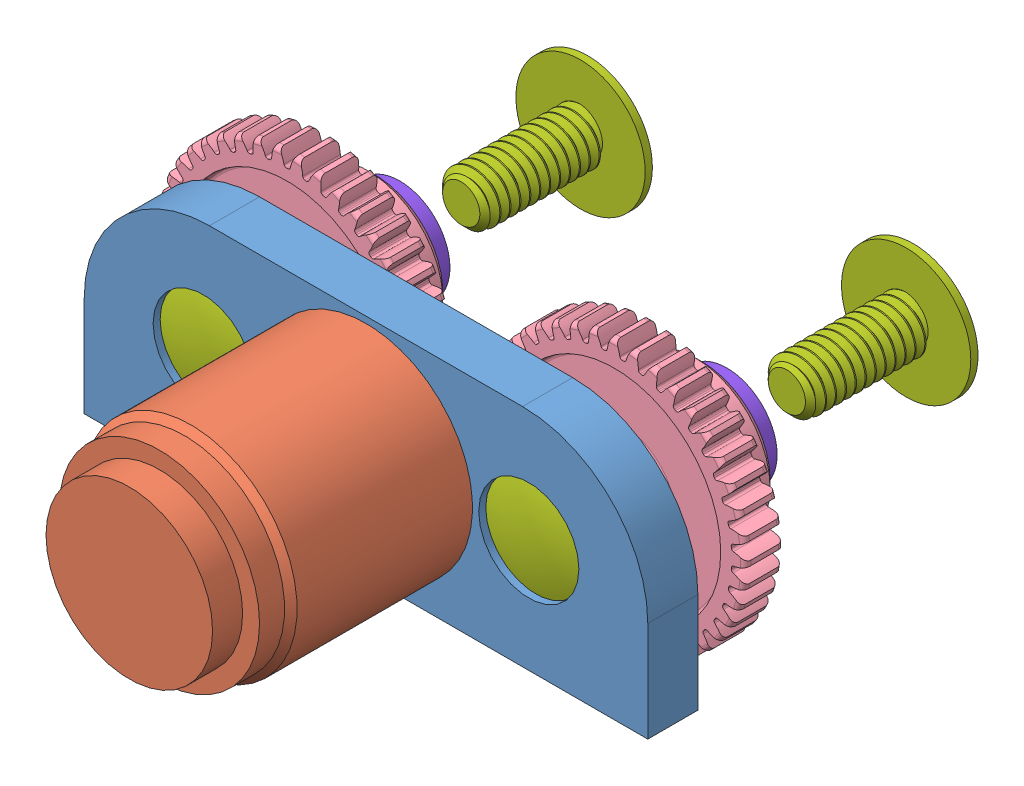
SolidWorks assembly motorassembly, configuration Default. Lengths in mm.
Overall size (55.17 29.38 50.59).
19 component instances, 9 part files, 31 mates.
Components (placement in the parent):
- smallmotormount-1: smallmotormount [Default] at (9.374 -3.21 4.9927) size (45 18 4)
- 1717SR-1: 1717SR [Default] at (-13.126 5.79 4.4927) size (17 17 28.5)
- 12g-1: 12g [Default] at (-13.126 5.79 -2.1073) x (0 0 1) z (-0.828983 0.559273 0) size (7.03 7.06 7.06)
- 40toothgearmod-1: 40toothgearmod [Default] at (-0.126 5.79 -3.3323) x (0 0 -1) z (0.582508 0.812825 0) size (7.03 21.05 21.05)
- 7804K104-1: 7804K104 [7804K104] at (-0.126 5.79 -3.2573) size (8 8 2.5)
- 7804K104-2: 7804K104 [7804K104] at (-0.126 5.79 -7.7073) size (8 8 2.5)
- 3mm spacer-1: 3mm spacer [93657A034] at (-0.126 5.79 -0.5073) x (0.468841 0.883283 0) z (0 0 1) size (8 8 3)
- 3mm spacer-2: 3mm spacer [93657A034] at (-26.126 5.79 -0.5073) size (8 8 3)
- 40toothgearmod-2: 40toothgearmod [Default] at (-26.126 5.79 -3.2073) x (0 0 -1) z (-0.852435 0.522834 0) size (7.03 21.05 21.05)
- 7804K104-3: 7804K104 [7804K104] at (-26.126 5.79 -7.4573) x (0.989675 -0.143329 0) z (0 0 1) size (8 8 2.5)
- 7804K104-4: 7804K104 [7804K104] at (-26.126 5.79 -3.5573) size (8 8 2.5)
- 93121A335-5: 93121A335 [93121A335] at (-26.126 5.79 -15.6123) x (0 0 -1) z (1 0 0) size (31.72 10.32 10.32)
- 93121A335-6: 93121A335 [93121A335] at (-0.126 5.79 -15.6123) x (0 0 -1) z (1 0 0) size (31.72 10.32 10.32)
- 2mm spacer-4: 2mm spacer [93657A031] at (-26.126 5.79 -9.7073) size (8 8 2)
- 2mm spacer-5: 2mm spacer [93657A031] at (-0.126 5.79 -9.8323) x (0.998742 -0.050146 0) z (0 0 1) size (8 8 2)
- 91430A003-1: 91430A003 [91430A003] at (-17.4561 3.29 1.9527) x (-0.81438 0.580333 0) z (0 0 -1) size (2.98 3 6.04)
- 91430A003-2: 91430A003 [91430A003] at (-8.7958 3.29 1.9527) x (-0.681464 0.731852 0) z (0 0 -1) size (2.98 3 6.04)
- 91430A003-3: 91430A003 [91430A003] at (-17.4561 8.29 1.9527) x (-0.939603 0.342267 0) z (0 0 -1) size (2.98 3 6.04)
- 91430A003-4: 91430A003 [91430A003] at (-8.7958 8.29 1.9527) x (-0.743466 0.668774 0) z (0 0 -1) size (2.98 3 6.04)
Mates (geometry in assembly coordinates):
- Concentric5: concentric aligned: cylinder of 1717SR-1 through (-13.126 5.79 -4.6073) axis (0 0 1) radius 0.75; cylinder of 12g-1 through (-13.126 5.79 -0.3073) axis (0 0 1) radius 1
- Concentric10: concentric anti-aligned: cylinder of 40toothgearmod-1 through (-0.126 5.79 -1.8035) axis (0 0 -1) radius 4; cylinder of 7804K104-1 through (-0.126 5.79 -2.0073) axis (0 0 1) radius 4
- Coincident13: coincident aligned: circle of 40toothgearmod-1; circle of 7804K104-1
- Concentric11: concentric anti-aligned: cylinder of 40toothgearmod-1 through (-0.126 5.79 -1.8035) axis (0 0 -1) radius 4; cylinder of 7804K104-2 through (-0.126 5.79 -6.4573) axis (0 0 1) radius 4
- Coincident14: coincident anti-aligned: circle of 40toothgearmod-1; circle of 7804K104-2
- Coincident23: coincident anti-aligned: plane of smallmotormount-1 through (9.374 14.79 0.9927) normal (0 0 -1); plane of 3mm spacer-1 through (-0.126 5.79 0.9927) normal (0 0 1)
- Coincident24: coincident anti-aligned: plane of 7804K104-1 through (-0.126 9.665 -2.0073) normal (0 0 1); plane of 3mm spacer-1 through (-0.126 5.79 -2.0073) normal (0 0 -1)
- Coincident26: coincident anti-aligned: plane of smallmotormount-1 through (9.374 14.79 0.9927) normal (0 0 -1); plane of 3mm spacer-2 through (-26.126 5.79 0.9927) normal (0 0 1)
- Coincident27: coincident anti-aligned: plane of 3mm spacer-2 through (-26.126 5.79 -2.0073) normal (0 0 -1); circle of 40toothgearmod-2
- Concentric22: concentric anti-aligned: cylinder of 40toothgearmod-2 through (-26.126 5.79 -1.6785) axis (0 0 -1) radius 4; cylinder of 7804K104-4 through (-26.126 5.79 -2.3073) axis (0 0 1) radius 4
- Concentric23: concentric aligned: circle of 40toothgearmod-2; circle of 7804K104-4
- Coincident28: coincident aligned: plane of 40toothgearmod-2 through (-26.126 5.79 -2.3073) normal (0 0 1); plane of 7804K104-4 through (-26.126 8.7983 -2.3073) normal (0 0 1)
- Concentric24: concentric anti-aligned: cylinder of 40toothgearmod-2 through (-26.126 5.79 -1.6785) axis (0 0 -1) radius 4; cylinder of 7804K104-3 through (-26.126 5.79 -6.2073) axis (0 0 1) radius 4
- Coincident30: coincident aligned: plane of 40toothgearmod-2 through (-26.126 5.79 -8.7073) normal (0 0 -1); plane of 7804K104-3 through (-25.7497 8.3879 -8.7073) normal (0 0 -1)
- Coincident31: coincident anti-aligned: plane of smallmotormount-1 through (-26.126 5.79 3.4377) normal (0 0 1); plane of 93121A335-5 through (-26.126 5.79 3.4377) normal (0 0 -1)
- Concentric26: concentric anti-aligned: cylinder of smallmotormount-1 through (-26.126 5.79 0.9927) axis (0 0 1) radius 2.5; cylinder of 93121A335-5 through (-26.126 5.79 0.2627) axis (0 0 -1) radius 2.5797
- Concentric27: concentric aligned: cylinder of 3mm spacer-2 through (-26.126 5.79 0.9927) axis (0 0 -1) radius 2.65; cylinder of 93121A335-5 through (-26.126 5.79 0.2627) axis (0 0 -1) radius 2.5797
- Concentric28: concentric anti-aligned: cylinder of 7804K104-4 through (-26.126 5.79 -2.3073) axis (0 0 1) radius 2.5; cylinder of 93121A335-5 through (-26.126 5.79 0.2627) axis (0 0 -1) radius 2.5797
- Coincident35: coincident anti-aligned: plane of smallmotormount-1 through (-0.126 5.79 3.4377) normal (0 0 1); plane of 93121A335-6 through (-0.126 5.79 3.4377) normal (0 0 -1)
- Concentric33: concentric aligned: cylinder of 3mm spacer-1 through (-0.126 5.79 0.9927) axis (0 0 -1) radius 2.65; cylinder of 93121A335-6 through (-0.126 5.79 0.2627) axis (0 0 -1) radius 2.5797
- Concentric34: concentric anti-aligned: cylinder of smallmotormount-1 through (-0.126 5.79 0.9927) axis (0 0 1) radius 2.5; cylinder of 93121A335-6 through (-0.126 5.79 0.2627) axis (0 0 -1) radius 2.5797
- Coincident36: coincident anti-aligned: plane of 7804K104-1 through (-0.126 8.7983 -2.0073) normal (0 0 1); plane of 3mm spacer-1 through (-0.126 5.79 -2.0073) normal (0 0 -1)
- Concentric35: concentric anti-aligned: cylinder of 7804K104-1 through (-0.126 5.79 -2.0073) axis (0 0 1) radius 2.5; cylinder of 93121A335-6 through (-0.126 5.79 0.2627) axis (0 0 -1) radius 2.5797
- Concentric36: concentric anti-aligned: circle of 93121A335-6; circle of 2mm spacer-5
- Concentric37: concentric anti-aligned: circle of 93121A335-5; circle of 2mm spacer-4
- Coincident39: coincident anti-aligned: plane of 7804K104-3 through (-25.7497 8.3879 -8.7073) normal (0 0 -1); plane of 2mm spacer-4 through (-26.126 5.79 -8.7073) normal (0 0 1)
- Coincident41: coincident anti-aligned: plane of 40toothgearmod-1 through (-0.126 5.79 -8.8323) normal (0 0 -1); plane of 2mm spacer-5 through (-0.126 5.79 -8.8323) normal (0 0 1)
- Coincident44: coincident aligned: cone of smallmotormount-1 through (-8.7958 8.29 0.9927) axis (0 0 1); cone of 91430A003-4 through (-8.7958 8.29 0.9927) axis (0 0 1)
- Coincident45: coincident aligned: cone of smallmotormount-1 through (-8.7958 3.29 0.9927) axis (0 0 1); cone of 91430A003-2 through (-8.7958 3.29 0.9927) axis (0 0 1)
- Coincident46: coincident aligned: cone of smallmotormount-1 through (-17.4561 8.29 0.9927) axis (0 0 1); cone of 91430A003-3 through (-17.4561 8.29 0.9927) axis (0 0 1)
- Coincident47: coincident aligned: cone of smallmotormount-1 through (-17.4561 3.29 0.9927) axis (0 0 1); cone of 91430A003-1 through (-17.4561 3.29 0.9927) axis (0 0 1)
